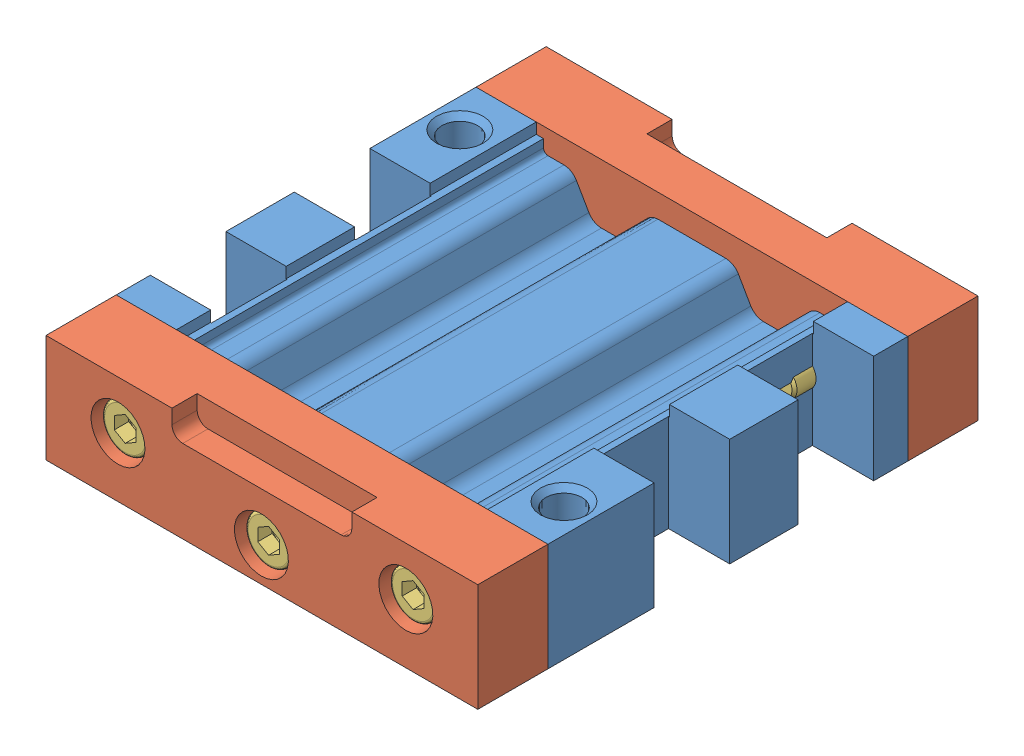
SolidWorks assembly сборка верхней пресс формы, configuration По умолчанию. Lengths in mm.
Overall size (120 30 139).
9 component instances, 3 part files, 18 mates.
Components (placement in the parent):
- Пуансон (на бис, дымись канабис)-1: Пуансон (на бис, дымись канабис) [По умолчанию] at (69.8379 150.2729 72.2482) x (-1 0 0) z (0 0 1) size (120 30 100)
- Боковина пуансона-1: Боковина пуансона [По умолчанию] at (82.3195 135.2729 132.0159) x (1 0 0) z (0 -1 0) size (120 19.5 30)
- Боковина пуансона-2: Боковина пуансона [По умолчанию] at (82.3195 135.2729 32.0159) x (-1 0 0) z (0 -1 0) size (120 19.5 30)
- болтец-1: болтец [EN ISO 4762 M8 x 25 - 25N] at (122.3195 136.7729 149.5159) x (0 0 -1) z (1 0 0) size (33 13 13)
- болтец-2: болтец [EN ISO 4762 M8 x 25 - 25N] at (82.18 129.7729 149.5159) x (0 0 -1) z (1 0 0) size (33 13 13)
- болтец-3: болтец [EN ISO 4762 M8 x 25 - 25N] at (42.3195 136.7729 149.5159) x (0 0 -1) z (1 0 0) size (33 13 13)
- болтец-4: болтец [EN ISO 4762 M8 x 25 - 25N] at (42.3195 136.7729 14.5159) x (0 0 1) z (-1 0 0) size (33 13 13)
- болтец-5: болтец [EN ISO 4762 M8 x 25 - 25N] at (82.4589 129.7729 14.5159) x (0 0 1) z (-1 0 0) size (33 13 13)
- болтец-6: болтец [EN ISO 4762 M8 x 25 - 25N] at (122.3195 136.7729 14.5159) x (0 0 1) z (-1 0 0) size (33 13 13)
Mates (geometry in assembly coordinates):
- Концентричный14: concentric aligned: cylinder of Пуансон (на бис, дымись канабис)-1 through (122.3195 136.7729 105.2659) axis (0 0 1) radius 3.4; cylinder of Боковина пуансона-1 through (122.3195 136.7729 151.5159) axis (0 0 1) radius 4.5
- Совпадение11: coincident anti-aligned: plane of Пуансон (на бис, дымись канабис)-1 through (142.3195 120.2729 132.0159) normal (0 0 1); plane of Боковина пуансона-1 through (82.3195 135.2729 132.0159) normal (0 0 -1)
- Концентричный15: concentric aligned: cylinder of Пуансон (на бис, дымись канабис)-1 through (122.3195 136.7729 58.7659) axis (0 0 -1) radius 3.4; cylinder of Боковина пуансона-2 through (122.3195 136.7729 12.5159) axis (0 0 -1) radius 4.5
- Совпадение12: coincident anti-aligned: plane of Пуансон (на бис, дымись канабис)-1 through (142.3195 120.2729 32.0159) normal (0 0 -1); plane of Боковина пуансона-2 through (82.3195 135.2729 32.0159) normal (0 0 1)
- Совпадение13: coincident aligned: plane of Пуансон (на бис, дымись канабис)-1 through (22.3195 120.2729 32.0159) normal (-1 0 0); plane of Боковина пуансона-1 through (22.3195 120.2729 151.5159) normal (-1 0 0)
- Совпадение14: coincident aligned: plane of Пуансон (на бис, дымись канабис)-1 through (22.3195 120.2729 32.0159) normal (-1 0 0); plane of Боковина пуансона-2 through (22.3195 120.2729 12.5159) normal (-1 0 0)
- Концентричный30: concentric aligned: cylinder of Боковина пуансона-1 through (122.3195 136.7729 151.5159) axis (0 0 1) radius 4.5; cylinder of socket head cap screw 4762_din-1 through (122.3195 136.7729 181.2659) axis (0 0 1) radius 6.5
- Совпадение30: coincident anti-aligned: plane of Боковина пуансона-1 through (126.8195 136.7729 141.5159) normal (0 0 1); plane of socket head cap screw 4762_din-1 through (122.3195 143.2729 141.5159) normal (0 0 -1)
- Концентричный31: concentric aligned: cylinder of Боковина пуансона-1 through (82.18 129.7729 151.5159) axis (0 0 1) radius 4.5; cylinder of socket head cap screw 4762_din-2 through (82.18 129.7729 181.2659) axis (0 0 1) radius 6.5
- Совпадение31: coincident anti-aligned: plane of Боковина пуансона-1 through (86.68 129.7729 141.5159) normal (0 0 1); plane of socket head cap screw 4762_din-2 through (82.18 136.2729 141.5159) normal (0 0 -1)
- Концентричный32: concentric aligned: cylinder of Боковина пуансона-1 through (42.3195 136.7729 151.5159) axis (0 0 1) radius 7.5; cylinder of socket head cap screw 4762_din-3 through (42.3195 136.7729 181.2659) axis (0 0 1) radius 6.5
- Совпадение32: coincident anti-aligned: plane of Боковина пуансона-1 through (46.8195 136.7729 141.5159) normal (0 0 1); plane of socket head cap screw 4762_din-3 through (42.3195 143.2729 141.5159) normal (0 0 -1)
- Концентричный33: concentric aligned: cylinder of Боковина пуансона-2 through (42.3195 136.7729 12.5159) axis (0 0 -1) radius 4.5; cylinder of socket head cap screw 4762_din-4 through (42.3195 136.7729 -17.2341) axis (0 0 -1) radius 6.5
- Совпадение33: coincident anti-aligned: plane of Боковина пуансона-2 through (37.8195 136.7729 22.5159) normal (0 0 -1); plane of socket head cap screw 4762_din-4 through (42.3195 143.2729 22.5159) normal (0 0 1)
- Концентричный34: concentric aligned: cylinder of Боковина пуансона-2 through (82.4589 129.7729 12.5159) axis (0 0 -1) radius 4.5; cylinder of socket head cap screw 4762_din-5 through (82.4589 129.7729 -17.2341) axis (0 0 -1) radius 6.5
- Совпадение34: coincident anti-aligned: plane of Боковина пуансона-2 through (77.9589 129.7729 22.5159) normal (0 0 -1); plane of socket head cap screw 4762_din-5 through (82.4589 136.2729 22.5159) normal (0 0 1)
- Концентричный35: concentric aligned: cylinder of Боковина пуансона-2 through (122.3195 136.7729 12.5159) axis (0 0 -1) radius 4.5; cylinder of socket head cap screw 4762_din-6 through (122.3195 136.7729 -17.2341) axis (0 0 -1) radius 6.5
- Совпадение35: coincident anti-aligned: plane of Боковина пуансона-2 through (117.8195 136.7729 22.5159) normal (0 0 -1); plane of socket head cap screw 4762_din-6 through (122.3195 143.2729 22.5159) normal (0 0 1)
